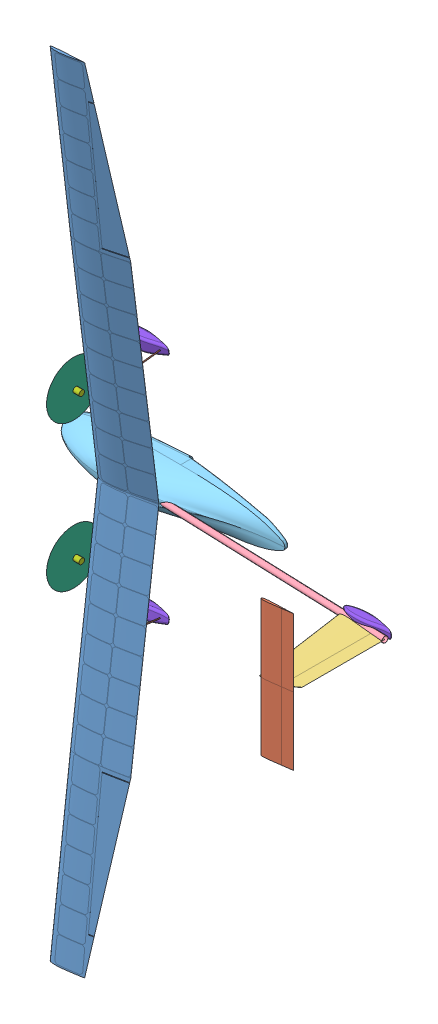
SolidWorks assembly seaway_mini, configuration Default. Lengths in mm.
Overall size (1788.65 4061.09 726.96).
18 component instances, 11 part files, 22 mates.
Components (placement in the parent):
- Wing-1: Wing [Default] at origin size (286.17 4061.09 285.91)
- HStab-1: HStab [Default] at origin size (154.02 695.63 484.74)
- VStab-1: VStab [Default] at origin size (240.42 28.42 488.56)
- Boom^seaway_mini-1: Boom^seaway_mini [Default] at origin size (1391.48 30.1 80.08) (virtual)
- pod_only-1: pod_only [Default] at (-78.9347 0 -180.8219) size (1117.92 199.12 247.21)
- Propeller^seaway_mini-1: Propeller^seaway_mini [Default] at origin size (0 279.4 279.4) (virtual)
- Propdrive v2 2830 800 kv Motor-1: Propdrive v2 2830 800 kv Motor [Default] at (-105.755 372.886 56.5042) x (0 1 0) z (0 0 1) size (28 45.1 28)
- Sponson Placeholder-1: Sponson Placeholder [Default] at (160 595.6682 -123.2511) x (0 -0.992546 -0.121869) z (-1 0 0) size (68.09 62.41 243.69)
- Sponson Placeholder-2: Sponson Placeholder [Default] at (1392.021 0 -30) x (0 -1 0) z (-1 0 0) size (68.09 62.41 243.69)
- Propeller^seaway_mini-2: Propeller^seaway_mini [Default] at (0 0 113.0085) x (1 0 0) z (0 0 -1) size (0 279.4 279.4) (virtual)
- Propdrive v2 2830 800 kv Motor-2: Propdrive v2 2830 800 kv Motor [Default] at (-105.755 -372.886 56.5042) x (0 -1 0) z (0 0 -1) size (28 45.1 28)
- Sponson Placeholder-4: Sponson Placeholder [Default] at (160 -595.6682 -123.2511) x (0 -0.992546 0.121869) z (-1 0 0) size (68.09 62.41 243.69)
- Inboard Sponson Mount^seaway_mini-3: Inboard Sponson Mount^seaway_mini [Default] at origin size (34.93 94.41 157.21) (virtual)
- Outboard Sponson Mount^seaway_mini-3: Outboard Sponson Mount^seaway_mini [Default] at origin size (34.93 54.8 173.39) (virtual)
- Aft Sponson Mount^seaway_mini-1: Aft Sponson Mount^seaway_mini [Default] at origin size (5.55 26.02 172.11) (virtual)
- Inboard Sponson Mount^seaway_mini-5: Inboard Sponson Mount^seaway_mini [Default] at (-30 -1054.2243 -36.2063) x (-1 0 0) z (0 0 -1) size (34.93 94.41 157.21) (virtual)
- Outboard Sponson Mount^seaway_mini-5: Outboard Sponson Mount^seaway_mini [Default] at (-30 -1273.5 -9.2826) x (-1 0 0) z (0 0 -1) size (34.93 54.8 173.39) (virtual)
- Aft Sponson Mount^seaway_mini-2: Aft Sponson Mount^seaway_mini [Default] at (249.4498 -1167.7379 -54.3073) x (-1 0 0) z (0 0 -1) size (5.55 26.02 172.11) (virtual)
Mates (geometry in assembly coordinates):
- Coincident1: coincident aligned: plane of pod_only-1 through (-78.9347 0 -180.8219) normal (0 1 0)
- Parallel1: parallel aligned: plane of pod_only-1 through (-78.9347 0 -180.8219) normal (0 0 1)
- Distance1: distance = 391.3194 mm: point of pod_only-1
- Coincident4: coincident aligned: plane of Wing^seaway_mini-1 through (0 0 26) normal (0 1 0)
- Parallel2: parallel aligned: plane of Wing^seaway_mini-1 through (0 0 26) normal (0 0 1)
- Coincident6: coincident: unknown of Wing^seaway_mini-1
- Distance3: distance = 26 mm: plane of Wing^seaway_mini-1 through (0 0 26) normal (0 0 1)
- Coincident7: coordinate: unknown of VStab-1
- Coincident13: coordinate: unknown of HStab-1
- Coincident14: coordinate: unknown of Wing-1
- Coincident17: coincident: unknown of pod_only-1
- Concentric1: concentric anti-aligned: circle of Propeller^seaway_mini-1; cylinder of Propdrive v2 2830 800 kv Motor-1 through (-136.755 372.886 56.5042) axis (1 0 0) radius 14
- Distance5: distance = 10 mm aligned: plane of Propdrive v2 2830 800 kv Motor-1 through (-136.755 372.886 56.5042) normal (-1 0 0); plane of Propeller^seaway_mini-1 through (-146.755 372.886 56.5042) normal (-1 0 0)
- Parallel6: parallel aligned: plane of Sponson Placeholder-1 through (160 595.6682 -123.2511) normal (0 -0.121869 0.992546); plane of Wing-1 through (0 0 0) normal (0 -0.121869 0.992546)
- Coincident21: coincident: point of pod_only-1; plane of Sponson Placeholder-1 through (160 595.6682 -123.2511) normal (0 -0.121869 0.992546)
- Distance6: distance = 80 mm: unknown of Sponson Placeholder-1
- Parallel7: parallel aligned: plane of Sponson Placeholder-2 through (1392.021 0 -30) normal (0 0 1)
- Coincident24: coincident anti-aligned: plane of Sponson Placeholder-2 through (1392.021 0 -30) normal (0 -1 0)
- Distance8: distance = 30 mm: unknown of Sponson Placeholder-2
- Coincident26: coincident: plane of Boom^seaway_mini-1 through (1390.428 0 14.2977) normal (0.999354 0 0.035938); point of Sponson Placeholder-2
- Parallel9: parallel anti-aligned: plane of Sponson Placeholder-1 through (160 595.6682 -123.2511) normal (-1 0 0)
- Distance9: distance = 500 mm: point of pod_only-1; plane of Sponson Placeholder-1 through (160 595.6682 -123.2511) normal (0 -0.992546 -0.121869)
